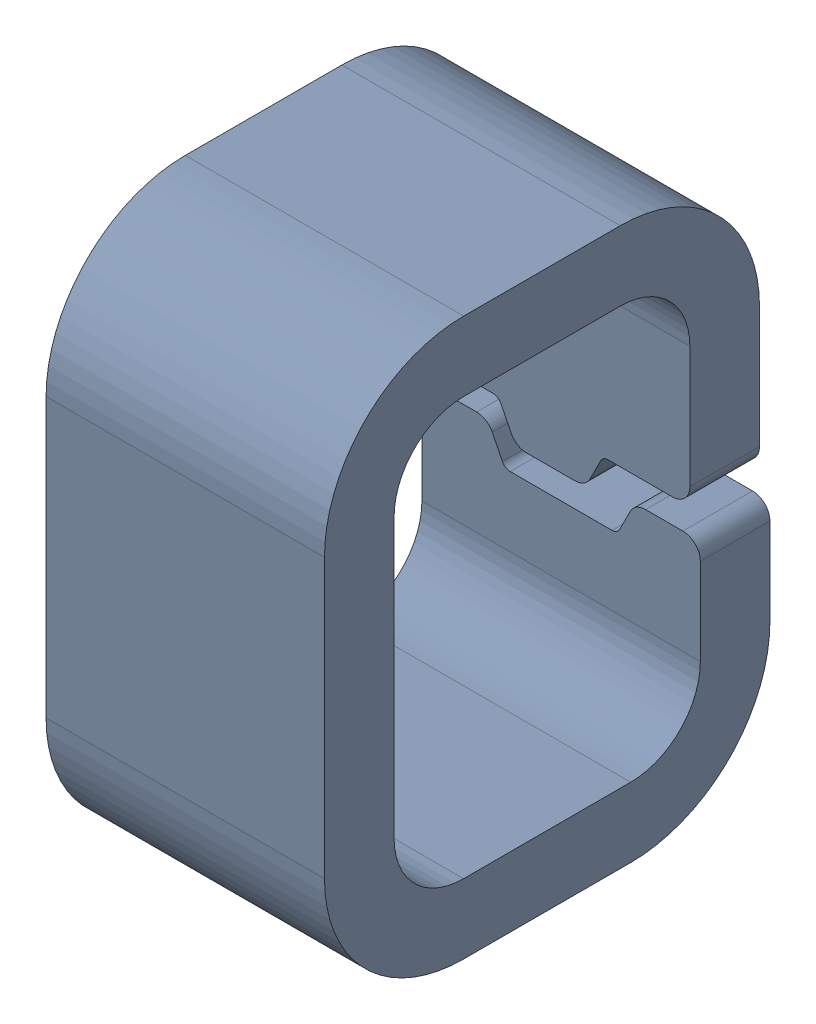
SolidWorks assembly TP3, configuration Default. Lengths in mm.
Overall size (0.8 1.6 1.28).
2 component instances, 1 part files, 0 mates.
Components (placement in the parent):
- Conn_Harwin_S2761-46R_eec-1: Conn_Harwin_S2761-46R_eec [Default] at (28.575 -6.858 0) x (0 -1 0) z (0 0 1) size (1.6 0.8 1.28)
  - TP-1: TP [Default] at origin size (1.6 0.8 1.28)
